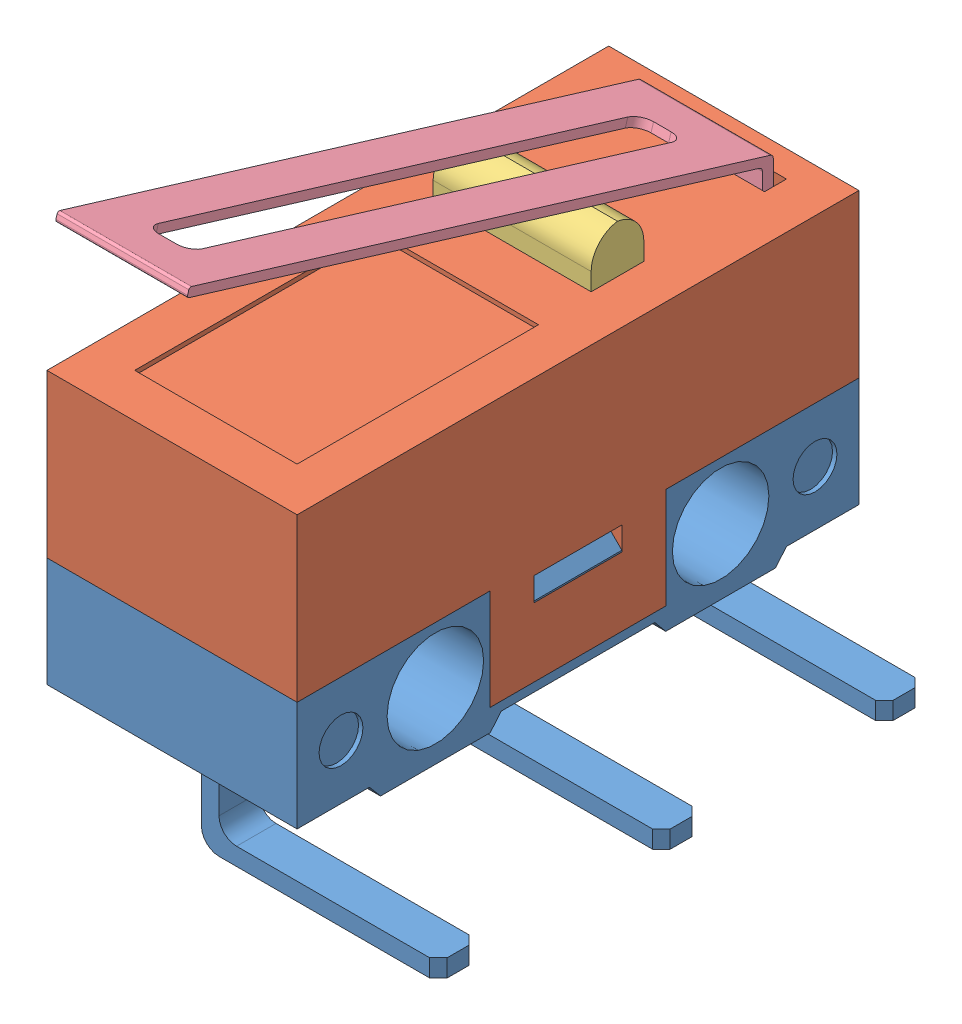
SolidWorks assembly Micro limit switch, configuration Default. Lengths in mm.
Overall size (8.15 12.86 13.95).
4 component instances, 4 part files, 0 mates.
Components (placement in the parent):
- PINS___ _________-1: PINS___ _________ [Default] at origin size (8.05 4.8 12.8)
- High_Part___ _________-1: High_Part___ _________ [Default] at origin size (5.8 6 12.8)
- Button___ _________-1: Button___ _________ [Default] at origin size (3.6 1.19 1.2)
- Plate-1: Plate [Default] at (4.35 6.2428 -1.95) x (0 0 1) z (-1 0 0) size (13.35 5.26 3)
